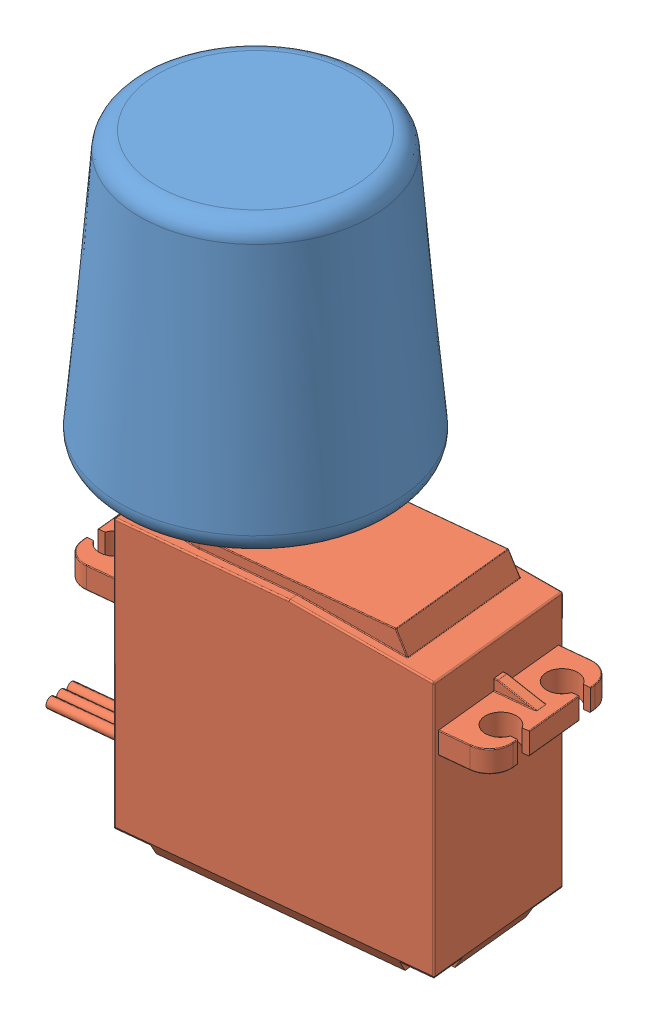
SolidWorks assembly Boelt Neck assem, configuration Default. Lengths in mm.
Overall size (63.93 84.13 45.14).
2 component instances, 2 part files, 1 mates.
Components (placement in the parent):
- Boelt Neck-1: Boelt Neck [Default] at origin size (41.91 38.1 45.14)
- sunfounder_20kgSLDPRT (1)-1: sunfounder_20kgSLDPRT (1) [Default] at (11.4225 -26.6277 8.8729) x (-0.102786 0 -0.994704) z (0.994704 0 -0.102786) size (20 46.03 62.2)
Mates (geometry in assembly coordinates):
- ProfileCenter4: profile center anti-aligned: circle of sunfounder_20kgSLDPRT (1)-1; plane of Boelt Neck-1 through (0 0 0) normal (0 -1 0)
